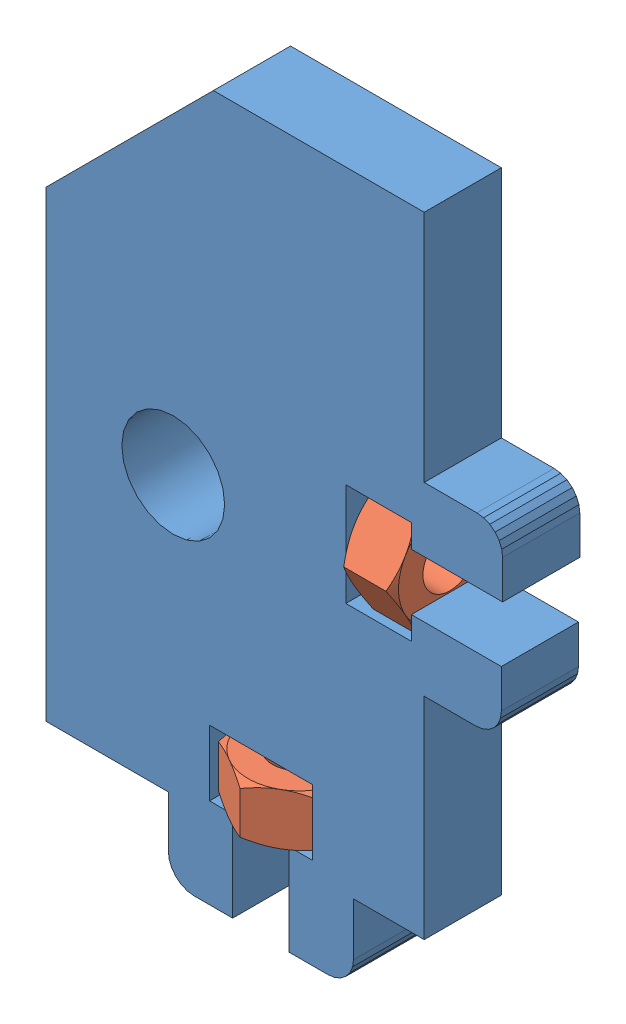
SolidWorks assembly Assembly Y-Idler side, configuration Valor predeterminado. Lengths in mm.
Overall size (35.5 55.1 11.55).
3 component instances, 2 part files, 11 mates.
Components (placement in the parent):
- Y-Idler-1: Y-Idler [Valor predeterminado] at (-45.7812 -37.3339 -3) size (35.5 55.1 6)
- Nut DIN 934 - M5-1: Nut DIN 934 - M5 [Valor predeterminado] at (0 -20.6 0) x (0 -1 0) z (-0.866025 0 -0.5) size (4 8 9.24)
- Nut DIN 934 - M5-2: Nut DIN 934 - M5 [Valor predeterminado] at (9.7 0 0) x (1 0 0) z (0 -0.866025 0.5) size (4 8 9.24)
Mates (geometry in assembly coordinates):
- Simétrico1: symmetric: plane of assembly; plane of assembly; plane of Y-Idler-1 through (-45.7812 -37.3339 3) normal (0 0 1); plane of Y-Idler-1 through (-45.7812 -37.3339 -3) normal (0 0 -1); plane of assembly
- Simétrico2: symmetric: plane of assembly; plane of assembly; plane of Y-Idler-1 through (11.7 2.2 3) normal (0 -1 0); plane of Y-Idler-1 through (11.7 -2.2 3) normal (0 1 0); plane of assembly
- Simétrico3: symmetric: plane of assembly; plane of assembly; plane of Y-Idler-1 through (-2.2 -22.6 3) normal (1 0 0); plane of Y-Idler-1 through (2.2 -22.6 3) normal (-1 0 0); plane of assembly
- Coincidente1: coincident: line of assembly; line of Nut DIN 934 - M5-1 through (0 -22.6 0) axis (0 1 0); plane of assembly
- Coincidente2: coincident: line of assembly; line of Nut DIN 934 - M5-1 through (0 -22.6 0) axis (0 1 0); plane of assembly
- Paralelo1: parallel: plane of assembly through (0 0 0) normal (1 0 0); plane of Nut DIN 934 - M5-1 through (4 -22.6 -2.3094) normal (1 0 0); plane of assembly
- Coincidente4: coincident: plane of assembly; plane of assembly; plane of Y-Idler-1 through (4 -22.6 3) normal (0 1 0); plane of Nut DIN 934 - M5-1 through (4 -22.6 -2.3094) normal (0 -1 0)
- Coincidente5: coincident: line of assembly; line of Nut DIN 934 - M5-2 through (11.7 0 0) axis (-1 0 0); plane of assembly
- Coincidente6: coincident: line of assembly; line of Nut DIN 934 - M5-2 through (11.7 0 0) axis (-1 0 0); plane of assembly
- Paralelo2: parallel: plane of assembly; plane of assembly; plane of Y-Idler-1 through (6.6 -4 3) normal (0 1 0); plane of Nut DIN 934 - M5-2 through (11.7 4 -2.3094) normal (0 1 0)
- Coincidente9: coincident: plane of assembly; plane of assembly; plane of Y-Idler-1 through (11.7 -4 3) normal (-1 0 0); plane of Nut DIN 934 - M5-2 through (11.7 0 -4.6188) normal (1 0 0)
